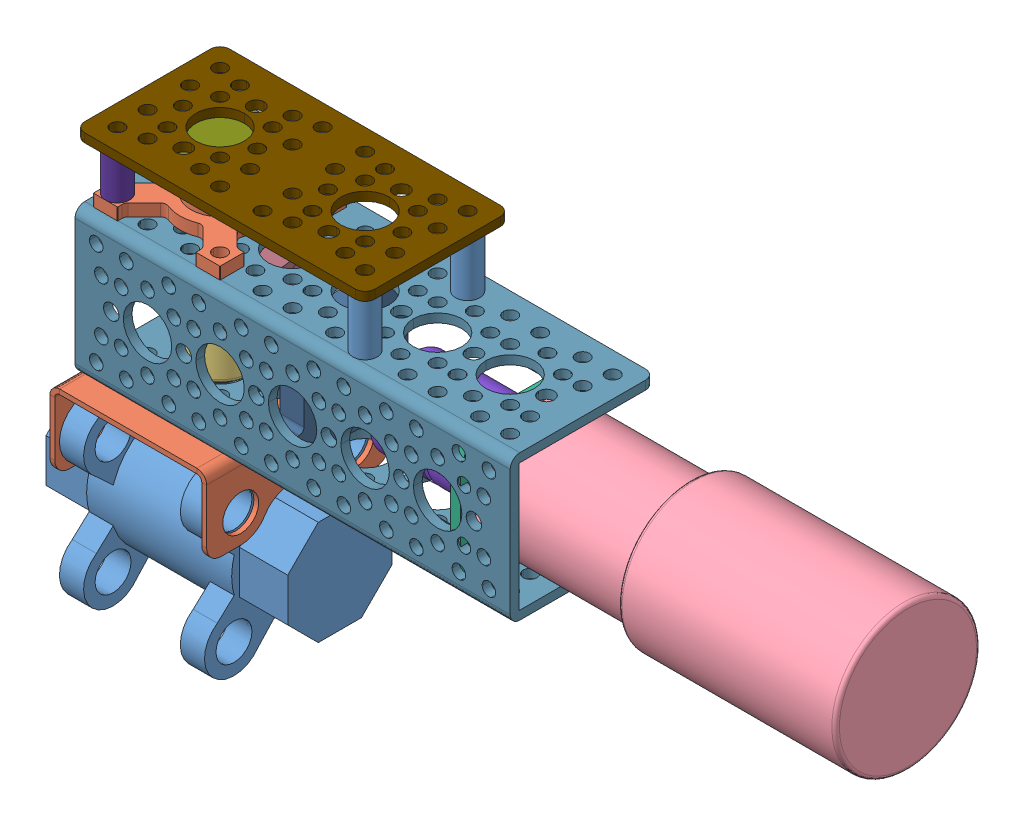
SolidWorks assembly MFV v3.2-customhub, configuration Default. Lengths in mm.
Overall size (212.44 107.57 48.16).
37 component instances, 22 part files, 45 mates.
Components (placement in the parent):
- Sharpe 39036-1: Sharpe 39036 [Default] at (-24.652 -21.0473 11.0376) size (63.5 64.02 45.72)
- 535110 assembly - Pillow-1: 535110 assembly - Pillow [Default] at (22.7078 30.253 4.1263) x (0 0 1) z (-1 0 0) size (33.27 5.08 33.27)
  - 535110 assembly - Pillow.STEP-1: 535110 assembly - Pillow.STEP [Default] at origin size (33.27 5.08 33.27)
    - 535110.STEP-1: 535110.STEP [Default] at (6.6273 15.2478 28.3097) size (33.27 5.08 33.27)
    - 535020.STEP-1: 535020.STEP [Default] at (6.6273 17.9338 28.3097) size (12.7 4.76 12.7)
- Motor_12VDC_638263-1: Motor_12VDC_638263 [Default] at (73.1868 26.5155 10.7536) x (0 -0.998999 -0.044744) z (0 0.044744 -0.998999) size (38 101.9 38)
- Motor_12VDC_638263_shaft-1: Motor_12VDC_638263_shaft [Default] at (73.1868 26.5155 10.7536) x (0 -0.998999 -0.044744) z (0 0.044744 -0.998999) size (6 16.2 6)
- 555188 assembly.STEP-1: 555188 assembly.STEP [Default] at (77.9607 32.9948 13.3688) x (0 1 0) z (0 0 1) size (33.4 16.56 37.36)
  - 555188.STEP-1: 555188.STEP [Default] at (-6.4793 1.7739 -2.6152) size (33.4 14.22 37.36)
  - 555188 screw_92005A116.STEP-1: 555188 screw_92005A116.STEP [Default] at (-15.6717 7.7739 6.5772) x (1 0 0) z (0 -1 0) size (6 6 8.35)
  - 555188 screw_92005A116.STEP-2: 555188 screw_92005A116.STEP [Default] at (2.7131 7.7739 6.5772) x (0 0 -1) z (0 -1 0) size (6 6 8.35)
  - 555188 screw_92005A116.STEP-3: 555188 screw_92005A116.STEP [Default] at (2.7131 7.7739 -11.8076) x (-1 0 0) z (0 -1 0) size (6 6 8.35)
  - 555188 screw_92005A116.STEP-4: 555188 screw_92005A116.STEP [Default] at (-15.6717 7.7739 -11.8076) x (0 0 1) z (0 -1 0) size (6 6 8.35)
- 625100 assembly.STEP-1: 625100 assembly.STEP [Default] at (78.1702 52.9589 35.3179) x (0 0.726073 0.687617) z (-1 0 0) size (50.01 22.2 75.17)
  - 625100.STEP-1: 625100.STEP [Default] at (-36.0907 -0.3474 4.9835) size (22.23 22.2 28.57)
  - 632112_90128A121.STEP-1: 632112_90128A121.STEP [Default] at (-1.3244 -7.8756 30.0025) x (0 0 -1) z (1 0 0) size (5.61 5.61 14.62)
  - 632112_90128A121.STEP-2: 632112_90128A121.STEP [Default] at (-1.3244 -7.8756 23.5255) x (0 0 -1) z (1 0 0) size (5.61 5.61 14.62)
  - 632112_90128A121.STEP-3: 632112_90128A121.STEP [Default] at (-1.3244 -7.8756 15.0165) x (0 0 -1) z (1 0 0) size (5.61 5.61 14.62)
  - 632112_90128A121.STEP-4: 632112_90128A121.STEP [Default] at (-1.3244 -7.8756 8.5395) x (0 0 -1) z (1 0 0) size (5.61 5.61 14.62)
- 535130 assembly.STEP-1: 535130 assembly.STEP [Default] at (9.528 18.8323 39.1453) x (0 1 0) z (0 0 -1) size (33.54 6.36 33.02)
  - 535130.STEP-1: 535130.STEP [Default] at (7.6184 14.2154 28.3917) size (33.54 6.36 33.02)
  - 535020.STEP-1: 535020.STEP [Default] at (7.6184 18.1715 28.3917) size (12.7 4.76 12.7)
- 615458 assembly.STEP-1: 615458 assembly.STEP [Default] at (-48.1481 51.8107 -4.4022) x (-1 0 0) z (0 -0.738394 0.67437) size (72.51 19.24 80.12)
  - 615458.STEP-1: 615458.STEP [Default] at (-61.4441 5.8673 28.8984) size (15.1 19.24 19.22)
  - 632110_90128A121.STEP-1: 632110_90128A121.STEP [Default] at (-66.148 1.368 -6.0266) x (-0.354662 -0.934995 0) z (0 0 -1) size (5.61 5.61 13.03)
- 615460.step-1: 615460.step [Default] at (-5.602 36.8057 10.7536) x (0 -1 0) z (-0.460247 0 -0.887791) size (8.04 33.75 33.87)
- 585444-1: 585444 [Default] at (-24.652 45.5007 29.8036) x (0 -1 0) z (1 0 0) size (38.1 38.1 114.3)
- D-shaft-2in-3: D-shaft-2in [Default] at (7.4008 26.5155 10.7536) x (0 -0.983443 -0.181218) z (0 -0.181218 0.983443) size (5.71 50.8 6.35)
- AS5047 eval board-1: AS5047 eval board [Default] at (-1.127 60.1057 10.8603) size (28 1.27 22)
- 0.5in standoff-2: 0.5in standoff [Default] at (-19.0724 48.6757 -2.7168) x (0.095865 0 0.995394) z (-0.995394 0 0.095865) size (6.35 12.7 6.35)
- 0.5in standoff-4: 0.5in standoff [Default] at (-19.0724 48.6757 24.224) x (0.320114 0 -0.947379) z (0.947379 0 0.320114) size (6.35 12.7 6.35)
- 585422.step-1: 585422.step [Default] at (13.448 61.3757 10.7536) size (76.2 2.29 38.1)
- .625in standoff-1: .625in standoff [Default] at (45.9684 61.3757 24.224) x (-0.852653 0 -0.522477) z (-0.522477 0 0.852653) size (6.35 15.88 6.35)
- .625in standoff-2: .625in standoff [Default] at (45.9684 45.5007 -2.7168) x (0.998481 0 -0.055099) z (0.055099 0 0.998481) size (6.35 15.88 6.35)
- Base v3.2-1: Base v3.2 [Default] at (-5.348 6.1307 11.0376) x (0 0 1) z (1 0 0) size (48.16 20.7 41.15)
- CustomHub-1: CustomHub [Default] at (-5.602 10.3375 10.7536) x (0.999286 0 -0.03778) z (0 1 0) size (20.32 20.32 22.86)
- D-shaft-1.25in-1: D-shaft-1.25in [Default] at (-5.602 52.2475 10.7536) x (-0.984016 0 -0.178081) z (-0.178081 0 0.984016) size (5.71 31.75 6.35)
Mates (geometry in assembly coordinates):
- Concentric8: concentric: circle of Motor_12VDC_638263-1; circle of Motor_12VDC_638263_shaft-1
- Coincident8: coincident: plane of Motor_12VDC_638263-1 through (73.1868 26.5155 10.7536) normal (-1 0 0); plane of Motor_12VDC_638263_shaft-1 through (73.1868 26.5155 10.7536) normal (1 0 0)
- Concentric10: concentric: cylinder of Motor_12VDC_638263-1 through (117.9868 26.5155 10.7536) axis (-1 0 0) radius 16; circle of 555188 assembly.STEP-1/555188.STEP-1
- Distance4: distance = 2.54 mm: plane of Motor_12VDC_638263-1 through (76.1868 26.5155 10.7536) normal (-1 0 0); plane of 555188 assembly.STEP-1/555188.STEP-1 through (73.6468 26.5155 10.7536) normal (-1 0 0)
- Concentric20: concentric: cylinder of Motor_12VDC_638263_shaft-1 through (56.9868 26.5155 10.7536) axis (1 0 0) radius 3; cylinder of 625100 assembly.STEP-1/625100.STEP-1 through (58.8993 26.5155 10.7536) axis (-1 0 0) radius 3
- Coincident25: coincident: plane of Motor_12VDC_638263-1 through (73.1868 26.5155 10.7536) normal (-1 0 0); plane of 625100 assembly.STEP-1/625100.STEP-1 through (73.1868 26.5155 10.7536) normal (1 0 0)
- Concentric22: concentric: cylinder of 625100 assembly.STEP-1/625100.STEP-1 through (58.8993 26.5155 10.7536) axis (-1 0 0) radius 3; cylinder of 615458 assembly.STEP-1/615458.STEP-1 through (6.4231 26.5155 10.7536) axis (1 0 0) radius 3
- Concentric25: concentric: cylinder of Sharpe 39036-1 through (-5.602 10.3375 10.7536) axis (0 -1 0) radius 4.6736; cylinder of 585444-1 through (-5.602 7.4007 10.7536) axis (0 -1 0) radius 6.3627
- Coincident34: coincident: plane of 535130 assembly.STEP-1/535130.STEP-1 through (30.0934 43.2147 -5.7564) normal (0 1 0); plane of 585444-1 through (89.648 43.2147 -8.2964) normal (0 -1 0)
- Concentric28: concentric: cylinder of 535130 assembly.STEP-1/535130.STEP-1 through (26.9184 43.2147 -2.7168) axis (0 1 0) radius 1.3526; cylinder of 585444-1 through (26.9184 7.4007 -2.7168) axis (0 -1 0) radius 1.778
- Concentric29: concentric: cylinder of 535130 assembly.STEP-1/535130.STEP-1 through (26.9184 43.2147 24.224) axis (0 1 0) radius 1.3526; cylinder of 585444-1 through (26.9184 7.4007 24.224) axis (0 -1 0) radius 1.778
- Concentric31: concentric: circle of 555188 assembly.STEP-1/555188.STEP-1; cylinder of 585444-1 through (65.0184 7.4007 -2.7168) axis (0 -1 0) radius 1.778
- Concentric32: concentric: cylinder of 625100 assembly.STEP-1/625100.STEP-1 through (58.8993 26.5155 10.7536) axis (-1 0 0) radius 3; cylinder of D-shaft-2in-3 through (58.2008 26.5155 10.7536) axis (-1 0 0) radius 3.175
- Coincident36: coincident: plane of 625100 assembly.STEP-1/625100.STEP-1 through (58.2008 10.8254 11.1603) normal (1 0 0); plane of D-shaft-2in-3 through (58.2008 26.5155 10.7536) normal (1 0 0)
- Concentric35: concentric: cylinder of 0.5in standoff-4 through (-19.0724 61.3757 24.224) axis (0 -1 0) radius 3.175; cylinder of 585422.step-1 through (-19.0724 63.6617 24.224) axis (0 1 0) radius 1.778
- Concentric36: concentric: cylinder of 0.5in standoff-2 through (-19.0724 61.3757 -2.7168) axis (0 -1 0) radius 3.175; cylinder of 585422.step-1 through (-19.0724 63.6617 -2.7168) axis (0 1 0) radius 1.778
- Coincident42: coincident: plane of 0.5in standoff-2 through (-19.0724 61.3757 -2.7168) normal (0 1 0); plane of 585422.step-1 through (13.448 61.3757 10.7536) normal (0 -1 0)
- Coincident43: coincident: plane of 585422.step-1 through (13.448 61.3757 10.7536) normal (0 -1 0); plane of .625in standoff-2 through (45.9684 61.3757 -2.7168) normal (0 1 0)
- Concentric38: concentric: circle of 585422.step-1; cylinder of .625in standoff-2 through (45.9684 61.3757 -2.7168) axis (0 -1 0) radius 3.175
- Concentric39: concentric: cylinder of .625in standoff-1 through (45.9684 45.5007 24.224) axis (0 1 0) radius 3.175; cylinder of 585422.step-1 through (45.9684 63.6617 24.224) axis (0 1 0) radius 1.778
- Coincident44: coincident: plane of 585422.step-1 through (13.448 61.3757 10.7536) normal (0 -1 0); plane of .625in standoff-1 through (45.9684 61.3757 24.224) normal (0 1 0)
- Coincident45: coincident: plane of AS5047 eval board-1 through (-1.127 61.3757 10.8603) normal (0 1 0); plane of 585422.step-1 through (13.448 61.3757 10.7536) normal (0 -1 0)
- Parallel4: parallel: line of AS5047 eval board-1 through (-15.127 61.3757 21.8603) axis (1 0 0); plane of 585422.step-1 through (-24.652 63.6617 29.8036) normal (0 0 1)
- Distance6: distance = 8.255 mm: line of AS5047 eval board-1 through (12.873 60.1057 -0.1397) axis (-1 0 0); line of 585422.step-1 through (49.008 61.3757 -8.2964) axis (-1 0 0)
- Coincident47: coincident: plane of D-shaft-2in-3 through (7.4008 26.5155 10.7536) normal (-1 0 0); plane of 615458 assembly.STEP-1/615458.STEP-1 through (7.4008 26.5155 10.7536) normal (-1 0 0)
- Coincident48: coincident: plane of 555188 assembly.STEP-1/555188.STEP-1 through (73.6468 43.2147 27.2128) normal (0 1 0); plane of 585444-1 through (89.648 43.2147 -8.2964) normal (0 -1 0)
- Concentric40: concentric: circle of 555188 assembly.STEP-1/555188.STEP-1; cylinder of 585444-1 through (65.0184 7.4007 24.224) axis (0 -1 0) radius 1.778
- Concentric41: concentric: cylinder of 585444-1 through (-19.0724 7.4007 -2.7168) axis (0 -1 0) radius 1.778; cylinder of 0.5in standoff-2 through (-19.0724 61.3757 -2.7168) axis (0 -1 0) radius 3.175
- Coincident49: coincident: plane of 0.5in standoff-4 through (-19.0724 61.3757 24.224) normal (0 1 0); plane of 585422.step-1 through (13.448 61.3757 10.7536) normal (0 -1 0)
- Concentric42: concentric: cylinder of 585444-1 through (-19.0724 7.4007 24.224) axis (0 -1 0) radius 1.778; cylinder of 0.5in standoff-4 through (-19.0724 61.3757 24.224) axis (0 -1 0) radius 3.175
- Distance7: distance = 3.175 mm: plane of 585444-1 through (89.648 45.5007 29.8036) normal (0 1 0); plane of 0.5in standoff-4 through (-19.0724 48.6757 24.224) normal (0 -1 0)
- Distance8: distance = 9.525 mm: plane of 585422.step-1 through (-24.652 63.6617 29.8036) normal (-1 0 0); plane of AS5047 eval board-1 through (-15.127 61.3757 -0.1397) normal (-1 0 0)
- Coincident52: coincident: plane of 535110 assembly - Pillow-1/535110 assembly - Pillow.STEP-1/535110.STEP-1 through (-5.602 45.5007 10.7536) normal (0 -1 0); plane of 585444-1 through (89.648 45.5007 29.8036) normal (0 1 0)
- Concentric45: concentric: cylinder of 535110 assembly - Pillow-1/535110 assembly - Pillow.STEP-1/535110.STEP-1 through (7.8684 48.6757 -2.7168) axis (0 1 0) radius 1.778; cylinder of 585444-1 through (7.8684 7.4007 -2.7168) axis (0 -1 0) radius 1.778
- Parallel5: parallel: cylinder of Sharpe 39036-1 through (-18.302 -21.0473 11.0376) axis (-1 0 0) radius 15.7226; line of 585444-1 through (87.108 7.4007 -8.2964) axis (-1 0 0)
- Coincident55: coincident: cylinder of Sharpe 39036-1 through (-18.302 -5.9343 -4.0754) axis (-1 0 0) radius 4.7307; circle of Base v3.2-1
- Concentric46: concentric: circle of Sharpe 39036-1; circle of Base v3.2-1
- Coincident57: coincident: plane of Sharpe 39036-1 through (-24.652 -21.0473 11.0376) normal (-1 0 0); plane of Base v3.2-1 through (-24.652 6.1307 11.0376) normal (1 0 0)
- Coincident58: coincident: plane of 585444-1 through (89.648 7.4007 -8.2964) normal (0 -1 0); plane of Base v3.2-1 through (-5.348 7.4007 11.0376) normal (0 1 0)
- Concentric49: concentric: circle of Sharpe 39036-1; cylinder of 615460.step-1 through (-5.602 30.9665 10.7536) axis (0 1 0) radius 3.175
- Concentric50: concentric: circle of Sharpe 39036-1; circle of CustomHub-1
- Coincident59: coincident: plane of 615460.step-1 through (-5.602 33.1975 10.7536) normal (0 -1 0); plane of CustomHub-1 through (-5.602 33.1975 10.7536) normal (0 1 0)
- Coincident62: coincident: plane of Sharpe 39036-1 through (-5.602 10.3375 10.7536) normal (0 1 0); plane of CustomHub-1 through (-5.602 10.3375 10.7536) normal (0 -1 0)
- Concentric51: concentric: cylinder of CustomHub-1 through (-5.602 23.0375 10.7536) axis (0 -1 0) radius 7.62; cylinder of D-shaft-1.25in-1 through (-5.602 21.0964 10.7536) axis (0 1 0) radius 3.175
- Coincident63: coincident: line of CustomHub-1 through (-7.6899 20.4975 8.278) axis (-0.999286 0 0.03778); plane of D-shaft-1.25in-1 through (-5.602 20.4975 10.7536) normal (0 -1 0)
